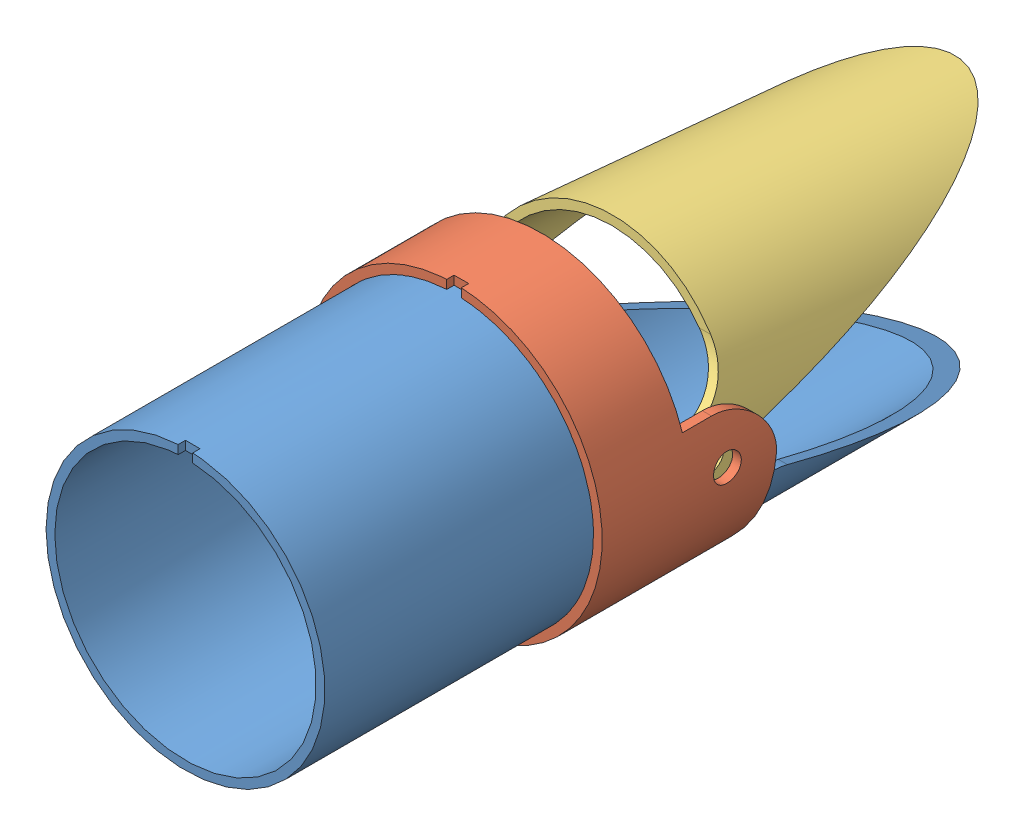
SolidWorks assembly Assem1, configuration Default. Lengths in mm.
Overall size (101.75 101.75 264.14).
3 component instances, 3 part files, 5 mates.
Components (placement in the parent):
- bottombeaktube-1: bottombeaktube [Default] at (-28.3347 52.9852 -21.0455) size (95.75 95.75 258)
- topbeakhingpoint-3: topbeakhingpoint [Default] at (-28.3347 52.9852 84.7536) size (101.75 101.75 60)
- top beak-1: top beak [Default] at (-28.3347 54.1994 114.4612) x (-1 0 0) z (0 -0.09512 -0.995466) size (89.75 58.59 138)
Mates (geometry in assembly coordinates):
- Concentric2: concentric aligned: cylinder of bottombeaktube-1 through (-28.3347 52.9852 236.9545) axis (0 0 -1) radius 47.875; cylinder of topbeakhingpoint-3 through (-28.3347 52.9852 144.7536) axis (0 0 -1) radius 47.875
- Distance2: distance = 0 mm aligned: plane of bottombeaktube-1 through (-76.2097 63.4473 114.7536) normal (0 0 -1); plane of topbeakhingpoint-3 through (31.6653 68.6321 114.7536) normal (0 0 -1)
- Parallel1: parallel aligned: plane of bottombeaktube-1 through (-30.8347 112.9852 239.4545) normal (1 0 0); plane of topbeakhingpoint-3 through (-30.8347 112.9852 147.2536) normal (1 0 0)
- Concentric3: concentric anti-aligned: cylinder of topbeakhingpoint-3 through (-79.2097 52.9852 101.7536) axis (1 0 0) radius 4.765; cylinder of top beak-1 through (16.5403 52.9852 101.7536) axis (-1 0 0) radius 4.765
- Distance4: distance = 6 mm aligned: plane of top beak-1 through (-73.2097 27.4237 -21.6089) normal (-1 0 0); cylinder of topbeakhingpoint-3 through (-28.3347 52.9852 144.7536) axis (0 0 -1) radius 50.875
